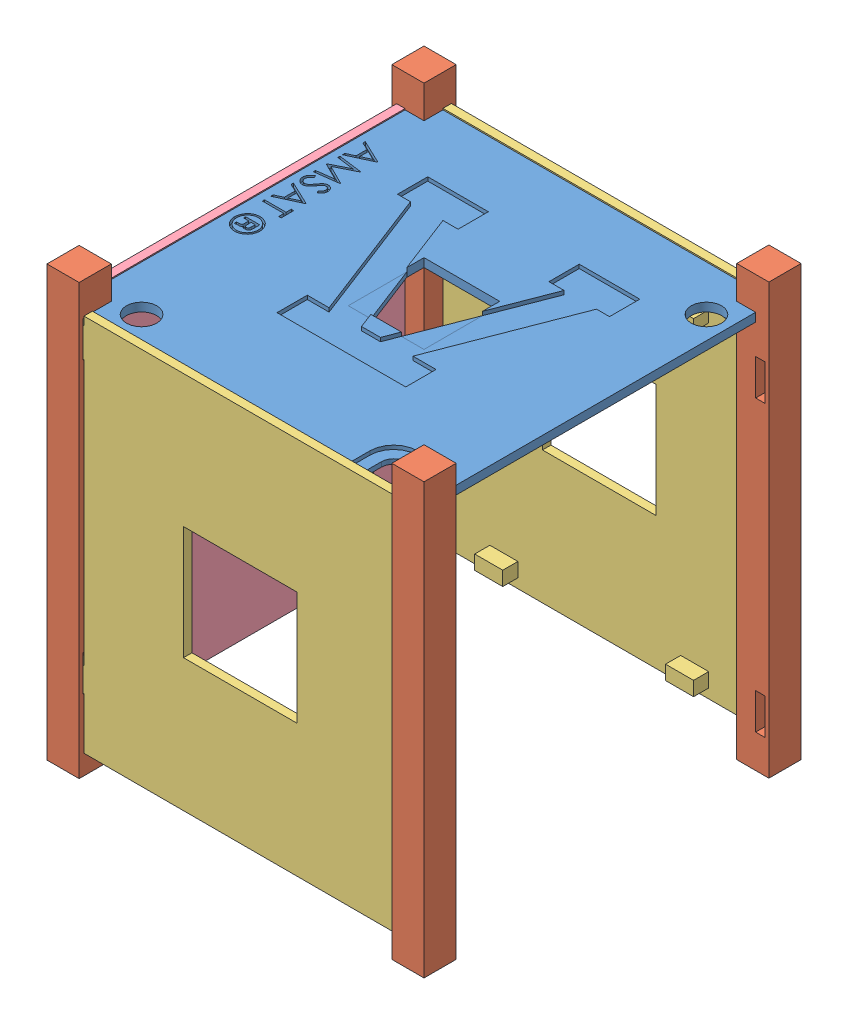
SolidWorks assembly Assem1, configuration Default. Lengths in mm.
Overall size (99.6 113.65 99.6).
8 component instances, 4 part files, 21 mates.
Components (placement in the parent):
- top-1: top [Default] at origin size (92.6 2.25 92.6)
- pillar-1: pillar [Default] at (45.55 -102.59 -45.55) size (8.5 113.5 8.5)
- pillar-2: pillar [Default] at (45.55 -102.74 45.55) x (0 0 1) z (-1 0 0) size (8.5 113.5 8.5)
- pillar-3: pillar [Default] at (-45.55 -102.64 -45.55) x (0 0 -1) z (1 0 0) size (8.5 113.5 8.5)
- pillar-4: pillar [Default] at (-45.55 -102.69 45.55) x (-1 0 0) z (0 0 -1) size (8.5 113.5 8.5)
- side_base-1: side_base [Default] at (0 -47.5 48.53) x (1 0 0) z (0 1 0) size (93 6.23 100)
- side-2: side [Default] at (-48.53 -47.45 0) x (0 0 1) z (0 1 0) size (93 2.23 100)
- side_base-2: side_base [Default] at (0 -47.4 -48.53) x (1 0 0) z (0 -1 0) size (93 6.23 100)
Mates (geometry in assembly coordinates):
- Coincident1: coincident anti-aligned: plane of top-1 through (41.3 2.25 0) normal (1 0 0); plane of pillar-1 through (41.3 10.91 -49.8) normal (-1 0 0)
- Coincident2: coincident anti-aligned: plane of top-1 through (0 2.25 -41.3) normal (0 0 -1); plane of pillar-1 through (41.3 10.91 -41.3) normal (0 0 1)
- Coincident4: coincident anti-aligned: plane of top-1 through (0 2.25 41.3) normal (0 0 1); plane of pillar-2 through (49.8 10.76 41.3) normal (0 0 -1)
- Coincident5: coincident anti-aligned: plane of top-1 through (41.3 2.25 0) normal (1 0 0); plane of pillar-2 through (41.3 10.76 41.3) normal (-1 0 0)
- Coincident8: coincident anti-aligned: plane of top-1 through (-41.3 2.25 0) normal (-1 0 0); plane of pillar-3 through (-41.3 10.86 -41.3) normal (1 0 0)
- Coincident9: coincident anti-aligned: plane of top-1 through (0 2.25 -41.3) normal (0 0 -1); plane of pillar-3 through (-49.8 10.86 -41.3) normal (0 0 1)
- Coincident10: coincident anti-aligned: plane of top-1 through (0 2.25 41.3) normal (0 0 1); plane of pillar-4 through (-41.3 10.81 41.3) normal (0 0 -1)
- Coincident11: coincident anti-aligned: plane of top-1 through (-41.3 2.25 0) normal (-1 0 0); plane of pillar-4 through (-41.3 10.81 49.8) normal (1 0 0)
- Coincident12: coincident anti-aligned: plane of side_base-1 through (41.3 -47.5 46.3) normal (1 0 0); plane of pillar-2 through (41.3 10.76 41.3) normal (-1 0 0)
- Coincident16: coincident anti-aligned: plane of top-1 through (0 2.25 46.3) normal (0 0 1); plane of side_base-1 through (0 -47.5 46.3) normal (0 0 -1)
- Coincident17: coincident aligned: line of pillar-2 through (41.3 -17.51 46.3) axis (0 0 1); line of side_base-1 through (41.3 -17.51 46.3) axis (0 0 1)
- Coincident18: coincident anti-aligned: line of pillar-4 through (-41.3 -7.49 48.8) axis (0 0 -1); line of side_base-1 through (-41.3 -7.49 46.3) axis (0 0 1)
- Coincident20: coincident anti-aligned: plane of top-1 through (0 0 0) normal (0 -1 0); plane of side_base-1 through (-21.5 0 42.3) normal (0 1 0)
- Coincident21: coincident anti-aligned: plane of pillar-4 through (-41.3 10.81 41.3) normal (0 0 -1); plane of side-2 through (-46.3 -47.45 41.3) normal (0 0 1)
- Coincident22: coincident aligned: line of pillar-4 through (-46.3 -17.46 41.3) axis (-1 0 0); line of side-2 through (-46.3 -17.46 41.3) axis (-1 0 0)
- Coincident24: coincident anti-aligned: plane of pillar-4 through (-46.3 -7.96 46.3) normal (-1 0 0); plane of side-2 through (-46.3 -47.45 0) normal (1 0 0)
- Coincident25: coincident anti-aligned: plane of pillar-3 through (-41.3 10.86 -41.3) normal (1 0 0); plane of side_base-2 through (-41.3 -47.4 -46.3) normal (-1 0 0)
- Coincident26: coincident anti-aligned: plane of pillar-3 through (-46.3 -7.91 -46.3) normal (0 0 -1); plane of side_base-2 through (0 -47.4 -46.3) normal (0 0 1)
- Coincident27: coincident aligned: line of pillar-3 through (-41.3 -17.41 -46.3) axis (0 0 -1); line of side_base-2 through (-41.3 -17.41 -46.3) axis (0 0 -1)
- Coincident28: coincident anti-aligned: line of pillar-3 through (-48.8 -7.44 -41.3) axis (1 0 0); line of side-2 through (-46.3 -7.44 -41.3) axis (-1 0 0)
- Coincident29: coincident anti-aligned: line of pillar-1 through (41.3 -7.39 -48.8) axis (0 0 1); line of side_base-2 through (41.3 -7.39 -46.3) axis (0 0 -1)
